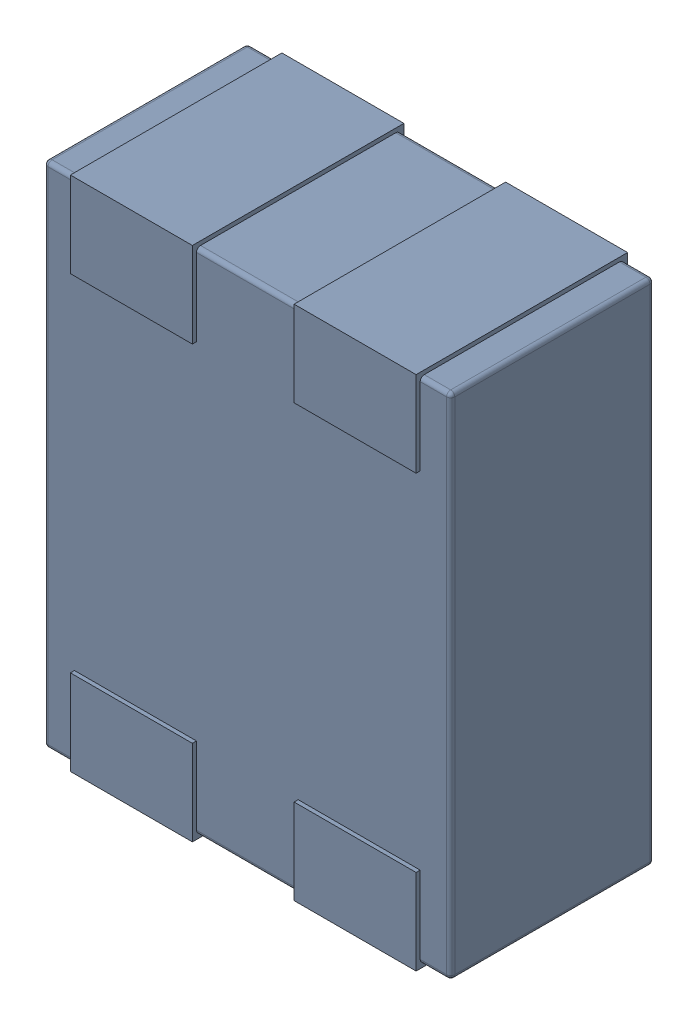
SolidWorks assembly L7, configuration Défaut. Lengths in mm.
Overall size (1 1.27 0.52).
4 component instances, 1 part files, 0 mates.
Components (placement in the parent):
- MCZ1210DH900L2TA0G-1: MCZ1210DH900L2TA0G [Défaut] at (44.1406 -40.5162 -1.6) x (-1 0 0) z (0 0 1) size (1 1.27 0.52)
  - 3D_PCB1_2021-12-30 (1).step-1: 3D_PCB1_2021-12-30 (1).step [Défaut] at origin size (1 1.27 0.52)
    - a3ec64f90eb5404ebd79eca0046a794a.step-1: a3ec64f90eb5404ebd79eca0046a794a.step [Défaut] at (5.0419 -6.8961 1.6) size (1 1.27 0.52)
      - SOLID.step_650-1: SOLID.step_650 [Défaut] at origin size (1 1.27 0.52)
